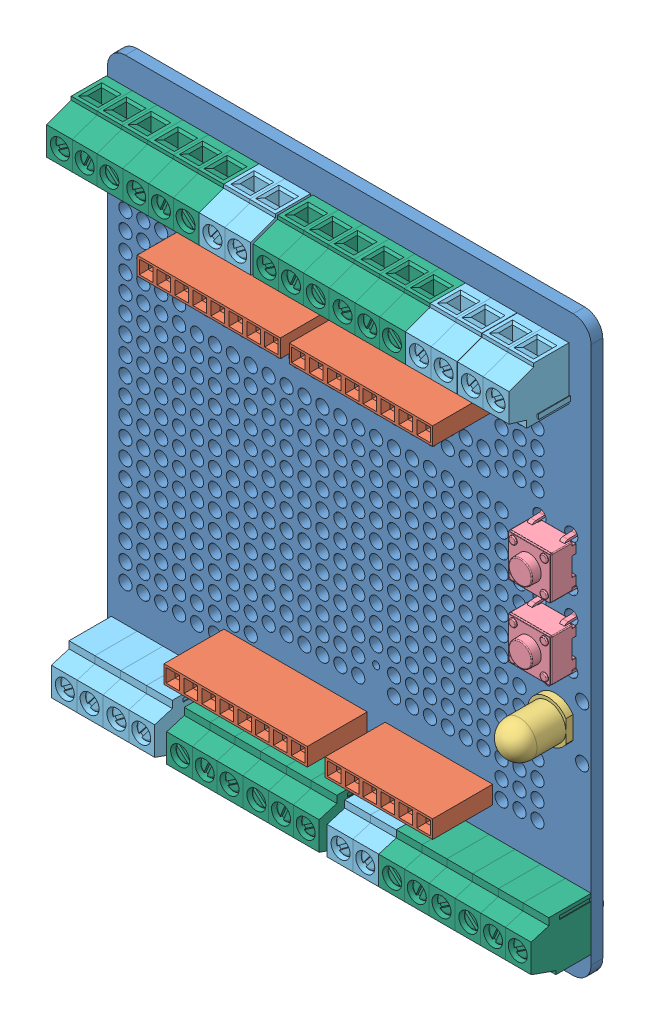
SolidWorks assembly ProtoScrewShield, configuration Default. Lengths in mm.
Overall size (68.72 81.28 18.96).
22 component instances, 6 part files, 72 mates.
Components (placement in the parent):
- ProtoScrewShield PCB-1: ProtoScrewShield PCB [Default] at (-66.799 -25.1325 5.7935) size (68.58 81.28 1.65)
- Female Header- Stackable-1: Female Header- Stackable [6 Pin] at (-13.459 -8.6225 15.9445) x (1 0 0) z (0 1 0) size (15.24 18.96 2.54)
- Female Header- Stackable-2: Female Header- Stackable [8 Pin] at (-31.239 -8.6225 15.9445) x (1 0 0) z (0 1 0) size (20.32 18.96 2.54)
- Female Header- Stackable-3: Female Header- Stackable [8 Pin] at (-13.459 39.6375 15.9445) x (1 0 0) z (0 1 0) size (20.32 18.96 2.54)
- Female Header- Stackable-4: Female Header- Stackable [8 Pin] at (-35.049 39.6375 15.9445) x (1 0 0) z (0 1 0) size (20.32 18.96 2.54)
- led_IR-1: led_IR [Trimmed Leads] at (-3.299 5.3286 927.0338) x (-1 0 0) z (0 1 0) size (5.45 10.78 5.9)
- tactileswitch-short-1: tactileswitch-short [Default] at (-3.3308 15.4536 7.4445) x (0 1 0) z (1 0 0) size (7.69 8.33 6.01)
- tactileswitch-short-2: tactileswitch-short [Default] at (-3.3308 25.5874 7.4445) x (0 1 0) z (1 0 0) size (7.69 8.33 6.01)
- 2 Pin PCB Terminal Block-1: 2 Pin PCB Terminal Block [Default] at (-62.4391 -17.5089 7.4445) x (-1 0 0) z (0 0 1) size (7.51 7.5 12)
- 3 Pin PCB Terminal Block-1: 3 Pin PCB Terminal Block [Default] at (-33.3793 -17.5089 7.4445) x (-1 0 0) z (0 0 1) size (11.01 7.5 12)
- 2 Pin PCB Terminal Block-2: 2 Pin PCB Terminal Block [Default] at (-55.1191 -17.5089 7.4445) x (-1 0 0) z (0 0 1) size (7.51 7.5 12)
- 3 Pin PCB Terminal Block-2: 3 Pin PCB Terminal Block [Default] at (-44.1893 -17.5089 7.4445) x (-1 0 0) z (0 0 1) size (11.01 7.5 12)
- 3 Pin PCB Terminal Block-3: 3 Pin PCB Terminal Block [Default] at (-14.124 -17.5089 7.4445) x (-1 0 0) z (0 0 1) size (11.01 7.5 12)
- 2 Pin PCB Terminal Block-4: 2 Pin PCB Terminal Block [Default] at (-23.349 -17.5089 7.4445) x (-1 0 0) z (0 0 1) size (7.51 7.5 12)
- 3 Pin PCB Terminal Block-5: 3 Pin PCB Terminal Block [Default] at (-3.314 -17.5089 7.4445) x (-1 0 0) z (0 0 1) size (11.01 7.5 12)
- 2 Pin PCB Terminal Block-5: 2 Pin PCB Terminal Block [Default] at (-5.1718 48.5238 7.4445) size (7.51 7.5 12)
- 2 Pin PCB Terminal Block-6: 2 Pin PCB Terminal Block [Default] at (-12.54 48.5238 7.4445) size (7.51 7.5 12)
- 3 Pin PCB Terminal Block-6: 3 Pin PCB Terminal Block [Default] at (-32.575 48.5238 7.4445) size (11.01 7.5 12)
- 2 Pin PCB Terminal Block-7: 2 Pin PCB Terminal Block [Default] at (-41.8046 48.5238 7.4445) size (7.51 7.5 12)
- 3 Pin PCB Terminal Block-7: 3 Pin PCB Terminal Block [Default] at (-21.765 48.5238 7.4445) size (11.01 7.5 12)
- 3 Pin PCB Terminal Block-8: 3 Pin PCB Terminal Block [Default] at (-51.0296 48.5238 7.4445) size (11.01 7.5 12)
- 3 Pin PCB Terminal Block-9: 3 Pin PCB Terminal Block [Default] at (-61.8396 48.5238 7.4445) size (11.01 7.5 12)
Mates (geometry in assembly coordinates):
- Coincident1: coincident anti-aligned: plane of ProtoScrewShield PCB-1 through (-0.759 53.6075 7.4445) normal (0 0 1); plane of Female Header- Stackable-4 through (-35.049 39.6375 7.4445) normal (0 0 -1)
- Width2: width: plane of Female Header- Stackable-4 through (-53.149 39.3175 -3.015) normal (-1 0 0); plane of Female Header- Stackable-4 through (-52.509 39.3175 -3.015) normal (1 0 0); cylinder of ProtoScrewShield PCB-1 through (-52.829 39.6375 7.4445) axis (0 0 -1) radius 0.9398
- Width3: width: plane of Female Header- Stackable-4 through (-52.509 39.3175 -3.015) normal (0 -1 0); plane of ProtoScrewShield PCB-1 through (-52.509 39.9575 -3.015) normal (0 1 0); cylinder of Female Header- Stackable-4 through (-52.829 39.6375 7.4445) axis (0 0 -1) radius 0.9398
- Parallel1: parallel aligned: plane of ProtoScrewShield PCB-1 through (-64.259 -25.1325 7.4445) normal (0 -1 0); plane of Female Header- Stackable-4 through (-33.779 38.3675 7.4445) normal (0 -1 0)
- Coincident2: coincident anti-aligned: plane of ProtoScrewShield PCB-1 through (-0.759 53.6075 7.4445) normal (0 0 1); plane of Female Header- Stackable-3 through (-13.459 39.6375 7.4445) normal (0 0 -1)
- Parallel2: parallel aligned: plane of Female Header- Stackable-3 through (-12.189 40.9075 7.4445) normal (0 1 0); plane of Female Header- Stackable-4 through (-33.779 40.9075 7.4445) normal (0 1 0)
- Width4: width: plane of Female Header- Stackable-3 through (-30.919 39.9575 -3.015) normal (0 1 0); plane of ProtoScrewShield PCB-1 through (-30.919 39.3175 -3.015) normal (0 -1 0); cylinder of Female Header- Stackable-3 through (-31.239 39.6375 7.4445) axis (0 0 -1) radius 0.9398
- Width5: width: plane of Female Header- Stackable-3 through (-31.559 39.3175 -3.015) normal (-1 0 0); plane of Female Header- Stackable-3 through (-30.919 39.3175 -3.015) normal (1 0 0); cylinder of ProtoScrewShield PCB-1 through (-31.239 39.6375 7.4445) axis (0 0 -1) radius 0.9398
- Coincident3: coincident anti-aligned: plane of ProtoScrewShield PCB-1 through (-0.759 53.6075 7.4445) normal (0 0 1); plane of Female Header- Stackable-1 through (-13.459 -8.6225 7.4445) normal (0 0 -1)
- Width6: width: plane of Female Header- Stackable-1 through (-13.139 -8.9425 -3.015) normal (1 0 0); plane of ProtoScrewShield PCB-1 through (-13.779 -8.9425 -3.015) normal (-1 0 0); cylinder of Female Header- Stackable-1 through (-13.459 -8.6225 7.4445) axis (0 0 -1) radius 0.9398
- Width7: width: plane of Female Header- Stackable-1 through (-13.139 -8.9425 -3.015) normal (0 -1 0); plane of ProtoScrewShield PCB-1 through (-13.139 -8.3025 -3.015) normal (0 1 0); cylinder of Female Header- Stackable-1 through (-13.459 -8.6225 7.4445) axis (0 0 -1) radius 0.9398
- Parallel3: parallel aligned: plane of Female Header- Stackable-1 through (-12.189 -9.8925 7.4445) normal (0 -1 0); plane of Female Header- Stackable-3 through (-12.189 38.3675 7.4445) normal (0 -1 0)
- Coincident4: coincident anti-aligned: plane of ProtoScrewShield PCB-1 through (-0.759 53.6075 7.4445) normal (0 0 1); plane of Female Header- Stackable-2 through (-31.239 -8.6225 7.4445) normal (0 0 -1)
- Parallel4: parallel aligned: plane of Female Header- Stackable-1 through (-12.189 -7.3525 7.4445) normal (0 1 0); plane of Female Header- Stackable-2 through (-29.969 -7.3525 7.4445) normal (0 1 0)
- Width8: width: plane of Female Header- Stackable-2 through (-30.919 -8.3025 -3.015) normal (0 1 0); plane of Female Header- Stackable-2 through (-30.919 -8.9425 -3.015) normal (0 -1 0); cylinder of ProtoScrewShield PCB-1 through (-31.239 -8.6225 7.4445) axis (0 0 -1) radius 0.9398
- Width9: width: plane of Female Header- Stackable-2 through (-31.559 -8.9425 -3.015) normal (-1 0 0); plane of ProtoScrewShield PCB-1 through (-30.919 -8.9425 -3.015) normal (1 0 0); cylinder of Female Header- Stackable-2 through (-31.239 -8.6225 7.4445) axis (0 0 -1) radius 0.9398
- Parallel5: parallel aligned: plane of ProtoScrewShield PCB-1 through (1.781 -22.5925 7.4445) normal (1 0 0); plane of led_IR-1 through (-0.799 7.8383 -16.9555) normal (1 0 0)
- Coincident6: coincident anti-aligned: plane of ProtoScrewShield PCB-1 through (-0.759 53.6075 7.4445) normal (0 0 1); plane of led_IR-1 through (-3.299 5.3286 7.4445) normal (0 0 -1)
- Width10: width: plane of led_IR-1 through (-1.779 5.0975 -17.9555) normal (1 0 0); plane of ProtoScrewShield PCB-1 through (-2.279 5.5975 -17.9555) normal (-1 0 0); cylinder of led_IR-1 through (-2.029 5.3475 7.4445) axis (0 0 -1) radius 0.9398
- Width11: width: plane of led_IR-1 through (-2.279 5.0975 -17.9555) normal (0 -1 0); plane of ProtoScrewShield PCB-1 through (-1.779 5.5975 -17.9555) normal (0 1 0); cylinder of led_IR-1 through (-2.029 5.3475 7.4445) axis (0 0 -1) radius 0.9398
- Coincident7: coincident anti-aligned: plane of ProtoScrewShield PCB-1 through (-0.759 53.6075 7.4445) normal (0 0 1); plane of tactileswitch-short-1 through (-0.3272 14.1518 7.4445) normal (0 0 -1)
- Parallel6: parallel aligned: plane of ProtoScrewShield PCB-1 through (1.781 -22.5925 7.4445) normal (1 0 0); plane of tactileswitch-short-1 through (-0.3272 12.45 10.8227) normal (1 0 0)
- Width12: width: plane of tactileswitch-short-1 through (-0.6828 18.1956 8.2546) normal (1 0 0); plane of ProtoScrewShield PCB-1 through (-1.394 18.1956 8.2546) normal (-1 0 0); cylinder of tactileswitch-short-1 through (-1.0384 18.7587 7.4445) axis (0 0 -1) radius 0.9398
- Distance1: distance = 37.5826 mm aligned: plane of tactileswitch-short-1 through (-0.3272 12.45 10.8227) normal (0 -1 0); plane of ProtoScrewShield PCB-1 through (-64.259 -25.1325 7.4445) normal (0 -1 0)
- Coincident9: coincident aligned: plane of tactileswitch-short-1 through (-0.3272 12.45 10.8227) normal (1 0 0); plane of tactileswitch-short-2 through (-0.3272 22.5838 10.8227) normal (1 0 0)
- Coincident10: coincident anti-aligned: plane of ProtoScrewShield PCB-1 through (-0.759 53.6075 7.4445) normal (0 0 1); plane of tactileswitch-short-2 through (-0.3272 24.2856 7.4445) normal (0 0 -1)
- Distance2: distance = 4.1267 mm anti-aligned: plane of tactileswitch-short-2 through (-0.3272 22.5838 10.8227) normal (0 -1 0); plane of tactileswitch-short-1 through (-0.3272 18.4571 10.8227) normal (0 1 0)
- Coincident12: coincident anti-aligned: plane of ProtoScrewShield PCB-1 through (-0.759 53.6075 7.4445) normal (0 0 1); plane of 2 Pin PCB Terminal Block-1 through (-66.2491 -13.7589 7.4445) normal (0 0 -1)
- Parallel8: parallel aligned: plane of ProtoScrewShield PCB-1 through (-66.799 -22.5925 7.4445) normal (-1 0 0); plane of 2 Pin PCB Terminal Block-1 through (-66.2491 -13.7589 7.4445) normal (-1 0 0)
- Coincident14: coincident anti-aligned: plane of 2 Pin PCB Terminal Block-1 through (-58.9291 -13.7589 7.4445) normal (1 0 0); plane of 2 Pin PCB Terminal Block-2 through (-58.9291 -13.7589 7.4445) normal (-1 0 0)
- Coincident15: coincident: plane of 2 Pin PCB Terminal Block-1 through (-66.2491 -21.2589 7.4445) normal (0 -1 0); plane of 2 Pin PCB Terminal Block-2 through (-58.9291 -21.2589 7.4445) normal (0 -1 0)
- Coincident16: coincident anti-aligned: plane of ProtoScrewShield PCB-1 through (-0.759 53.6075 7.4445) normal (0 0 1); plane of 2 Pin PCB Terminal Block-2 through (-58.9291 -13.7589 7.4445) normal (0 0 -1)
- Width17: width: plane of 2 Pin PCB Terminal Block-1 through (-63.9437 -17.7625 3.9445) normal (0 -1 0); plane of ProtoScrewShield PCB-1 through (-64.7444 -17.2625 3.9445) normal (0 1 0); cylinder of 2 Pin PCB Terminal Block-1 through (-64.2591 -17.5125 7.4445) axis (0 0 -1) radius 1.016
- Coincident18: coincident: plane of 3 Pin PCB Terminal Block-1 through (-39.0943 -15.5089 15.9445) normal (0 0.957826 0.287348); plane of 3 Pin PCB Terminal Block-2 through (-49.9043 -15.5089 15.9445) normal (0 0.957826 0.287348)
- Coincident19: coincident: plane of 3 Pin PCB Terminal Block-1 through (-39.0943 -13.7589 7.4445) normal (0 1 0); plane of 3 Pin PCB Terminal Block-2 through (-49.9043 -13.7589 7.4445) normal (0 1 0)
- Coincident20: coincident anti-aligned: plane of 3 Pin PCB Terminal Block-1 through (-39.0943 -13.7589 7.4445) normal (-1 0 0); plane of 3 Pin PCB Terminal Block-2 through (-39.0943 -13.7589 7.4445) normal (1 0 0)
- Coincident21: coincident anti-aligned: plane of ProtoScrewShield PCB-1 through (-0.759 53.6075 7.4445) normal (0 0 1); plane of 3 Pin PCB Terminal Block-1 through (-39.0943 -13.7589 7.4445) normal (0 0 -1)
- Coincident22: coincident: plane of 2 Pin PCB Terminal Block-2 through (-58.9291 -21.2589 7.4445) normal (0 -1 0); plane of 3 Pin PCB Terminal Block-2 through (-49.9043 -21.2589 7.4445) normal (0 -1 0)
- Coincident26: coincident anti-aligned: plane of ProtoScrewShield PCB-1 through (-0.759 53.6075 7.4445) normal (0 0 1); plane of 3 Pin PCB Terminal Block-3 through (-19.839 -13.7589 7.4445) normal (0 0 -1)
- Coincident27: coincident: plane of 3 Pin PCB Terminal Block-1 through (-39.0943 -21.2589 7.4445) normal (0 -1 0); plane of 3 Pin PCB Terminal Block-3 through (-19.839 -21.2589 7.4445) normal (0 -1 0)
- Coincident28: coincident anti-aligned: plane of 3 Pin PCB Terminal Block-3 through (-19.839 -13.7589 7.4445) normal (-1 0 0); plane of 2 Pin PCB Terminal Block-4 through (-19.839 -13.7589 7.4445) normal (1 0 0)
- Coincident31: coincident: plane of 3 Pin PCB Terminal Block-3 through (-19.839 -20.7589 12.4445) normal (0 -0.941742 0.336336); plane of 2 Pin PCB Terminal Block-4 through (-27.159 -20.7589 12.4445) normal (0 -0.941742 0.336336)
- Coincident32: coincident: plane of 3 Pin PCB Terminal Block-3 through (-19.839 -15.5089 15.9445) normal (0 0 1); plane of 2 Pin PCB Terminal Block-4 through (-27.159 -15.5089 15.9445) normal (0 0 1)
- Coincident34: coincident: plane of 3 Pin PCB Terminal Block-3 through (-19.839 -20.7589 12.4445) normal (0 -0.941742 0.336336); plane of 3 Pin PCB Terminal Block-5 through (-9.029 -20.7589 12.4445) normal (0 -0.941742 0.336336)
- Coincident35: coincident: plane of 3 Pin PCB Terminal Block-3 through (-19.839 -15.5089 15.9445) normal (0 0 1); plane of 3 Pin PCB Terminal Block-5 through (-9.029 -15.5089 15.9445) normal (0 0 1)
- Coincident36: coincident: plane of 3 Pin PCB Terminal Block-3 through (-19.839 -21.2589 7.4445) normal (0 -1 0); plane of 3 Pin PCB Terminal Block-5 through (-9.029 -21.2589 7.4445) normal (0 -1 0)
- Coincident37: coincident anti-aligned: plane of 3 Pin PCB Terminal Block-3 through (-9.029 -13.7589 7.4445) normal (1 0 0); plane of 3 Pin PCB Terminal Block-5 through (-9.029 -13.7589 7.4445) normal (-1 0 0)
- Distance4: distance = 0.55 mm aligned: plane of 2 Pin PCB Terminal Block-1 through (-66.2491 -13.7589 7.4445) normal (-1 0 0); plane of ProtoScrewShield PCB-1 through (-66.799 -22.5925 7.4445) normal (-1 0 0)
- Distance5: distance = 1.7048 mm anti-aligned: plane of 3 Pin PCB Terminal Block-2 through (-49.9043 -13.7589 7.4445) normal (-1 0 0); plane of 2 Pin PCB Terminal Block-2 through (-51.6091 -13.7589 7.4445) normal (1 0 0)
- Coincident38: coincident aligned: plane of ProtoScrewShield PCB-1 through (1.781 -22.5925 7.4445) normal (1 0 0); plane of 3 Pin PCB Terminal Block-5 through (1.781 -13.7589 7.4445) normal (1 0 0)
- Coincident39: coincident anti-aligned: plane of ProtoScrewShield PCB-1 through (-0.759 53.6075 7.4445) normal (0 0 1); plane of 2 Pin PCB Terminal Block-5 through (-1.0618 44.7738 7.4445) normal (0 0 -1)
- Parallel9: parallel aligned: plane of ProtoScrewShield PCB-1 through (-64.259 56.1475 7.4445) normal (0 1 0); plane of 2 Pin PCB Terminal Block-5 through (-1.0618 52.2738 7.4445) normal (0 1 0)
- Width18: width: plane of 2 Pin PCB Terminal Block-5 through (-6.3764 48.7775 3.9445) normal (0 1 0); plane of 2 Pin PCB Terminal Block-5 through (-7.1772 48.2775 3.9445) normal (0 -1 0); cylinder of ProtoScrewShield PCB-1 through (-6.799 48.5275 7.4445) axis (0 0 -1) radius 1.016
- Distance6: distance = 3.1428 mm aligned: plane of 2 Pin PCB Terminal Block-5 through (-1.3618 44.7738 7.4445) normal (1 0 0); plane of ProtoScrewShield PCB-1 through (1.781 -22.5925 7.4445) normal (1 0 0)
- Coincident41: coincident anti-aligned: plane of 3 Pin PCB Terminal Block-6 through (-26.86 44.7738 7.4445) normal (1 0 0); plane of 3 Pin PCB Terminal Block-7 through (-26.86 44.7738 7.4445) normal (-1 0 0)
- Coincident42: coincident aligned: plane of 3 Pin PCB Terminal Block-6 through (-26.86 44.7738 7.4445) normal (0 -1 0); plane of 3 Pin PCB Terminal Block-7 through (-15.43 44.7738 7.4445) normal (0 -1 0)
- Coincident43: coincident aligned: plane of 3 Pin PCB Terminal Block-6 through (-26.86 46.5238 15.9445) normal (0 0 1); plane of 3 Pin PCB Terminal Block-7 through (-15.43 46.5238 15.9445) normal (0 0 1)
- Coincident47: coincident anti-aligned: plane of 2 Pin PCB Terminal Block-6 through (-16.05 44.7738 7.4445) normal (-1 0 0); plane of 3 Pin PCB Terminal Block-7 through (-16.05 44.7738 7.4445) normal (1 0 0)
- Coincident48: coincident aligned: plane of 2 Pin PCB Terminal Block-6 through (-8.43 44.7738 7.4445) normal (0 -1 0); plane of 3 Pin PCB Terminal Block-7 through (-16.05 44.7738 7.4445) normal (0 -1 0)
- Coincident49: coincident aligned: plane of 2 Pin PCB Terminal Block-6 through (-8.43 46.5238 15.9445) normal (0 0 1); plane of 3 Pin PCB Terminal Block-7 through (-16.05 46.5238 15.9445) normal (0 0 1)
- Coincident50: coincident anti-aligned: plane of ProtoScrewShield PCB-1 through (-0.759 53.6075 7.4445) normal (0 0 1); plane of 2 Pin PCB Terminal Block-6 through (-8.73 44.7738 7.4445) normal (0 0 -1)
- Coincident51: coincident aligned: plane of 2 Pin PCB Terminal Block-5 through (-1.0618 52.2738 7.4445) normal (0 1 0); plane of 3 Pin PCB Terminal Block-6 through (-26.24 52.2738 7.4445) normal (0 1 0)
- Distance7: distance = 0.0482 mm anti-aligned: plane of 2 Pin PCB Terminal Block-5 through (-8.6818 44.7738 7.4445) normal (-1 0 0); plane of 2 Pin PCB Terminal Block-6 through (-8.73 44.7738 7.4445) normal (1 0 0)
- Coincident52: coincident anti-aligned: plane of ProtoScrewShield PCB-1 through (-0.759 53.6075 7.4445) normal (0 0 1); plane of 2 Pin PCB Terminal Block-7 through (-37.6946 44.7738 7.4445) normal (0 0 -1)
- Coincident53: coincident aligned: plane of 3 Pin PCB Terminal Block-6 through (-26.24 52.2738 7.4445) normal (0 1 0); plane of 2 Pin PCB Terminal Block-7 through (-37.9946 52.2738 7.4445) normal (0 1 0)
- Coincident54: coincident anti-aligned: plane of 2 Pin PCB Terminal Block-7 through (-45.3146 44.7738 7.4445) normal (-1 0 0); plane of 3 Pin PCB Terminal Block-8 through (-45.3146 44.7738 7.4445) normal (1 0 0)
- Coincident55: coincident anti-aligned: plane of 3 Pin PCB Terminal Block-8 through (-56.1246 44.7738 7.4445) normal (-1 0 0); plane of 3 Pin PCB Terminal Block-9 through (-56.1246 44.7738 7.4445) normal (1 0 0)
- Coincident56: coincident aligned: plane of 3 Pin PCB Terminal Block-8 through (-44.6946 52.2738 7.4445) normal (0 1 0); plane of 3 Pin PCB Terminal Block-9 through (-56.1246 52.2738 7.4445) normal (0 1 0)
- Coincident57: coincident aligned: plane of 2 Pin PCB Terminal Block-7 through (-37.6946 52.2738 7.4445) normal (0 1 0); plane of 3 Pin PCB Terminal Block-8 through (-45.3146 52.2738 7.4445) normal (0 1 0)
- Coincident58: coincident aligned: plane of 2 Pin PCB Terminal Block-7 through (-37.6946 46.5238 15.9445) normal (0 0 1); plane of 3 Pin PCB Terminal Block-8 through (-45.3146 46.5238 15.9445) normal (0 0 1)
- Coincident59: coincident aligned: plane of 3 Pin PCB Terminal Block-8 through (-44.6946 46.5238 15.9445) normal (0 0 1); plane of 3 Pin PCB Terminal Block-9 through (-56.1246 46.5238 15.9445) normal (0 0 1)
- Distance8: distance = 0.3246 mm anti-aligned: plane of 3 Pin PCB Terminal Block-6 through (-37.67 44.7738 7.4445) normal (-1 0 0); plane of 2 Pin PCB Terminal Block-7 through (-37.9946 44.7738 7.4445) normal (1 0 0)
